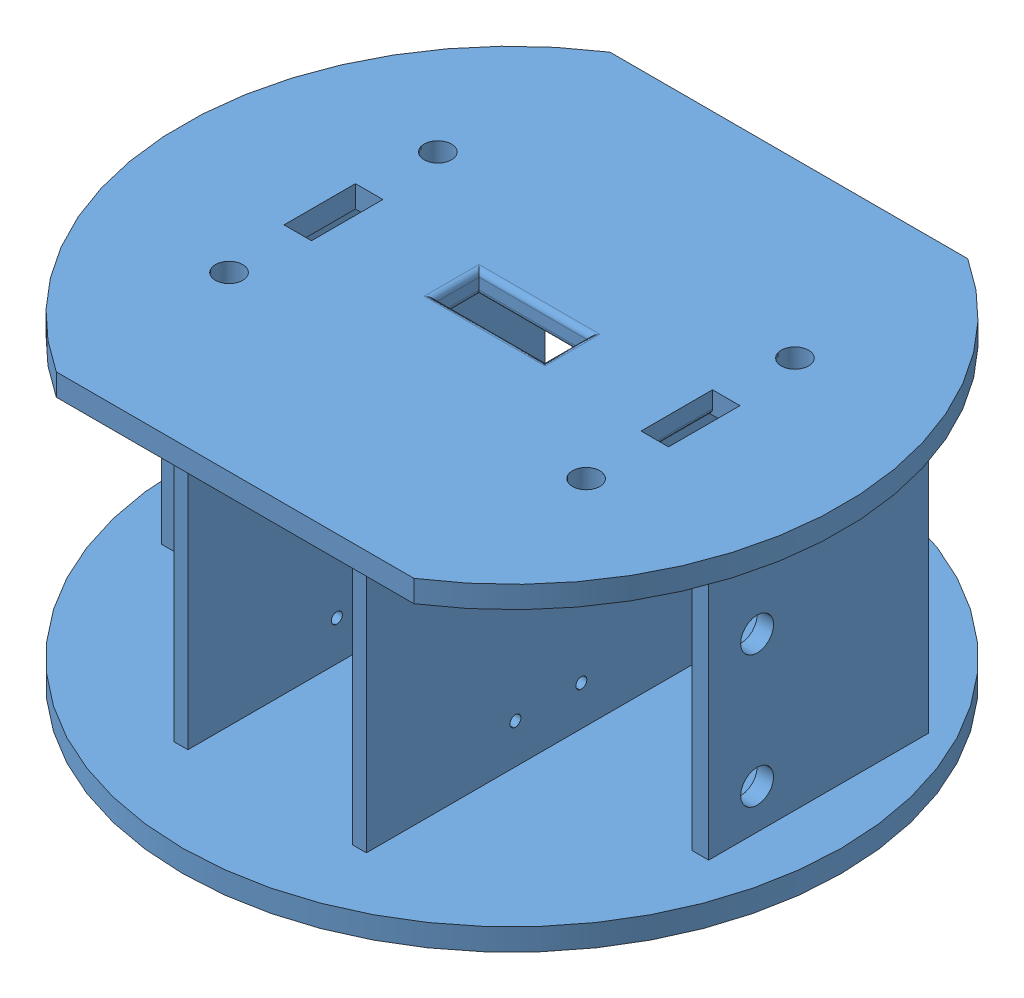
SolidWorks assembly NewMainBase, configuration Default. Lengths in mm.
Overall size (120 71.5 120).
2 component instances, 2 part files, 1 mates.
Components (placement in the parent):
- Main_Base-1: Main_Base [Default] at origin size (120 58 120)
- dovetail_female-1: dovetail_female [Default] at (0 -60.75 0) size (49 13.5 60)
Mates (geometry in assembly coordinates):
- Coincident1: coincident: point of dovetail_female-1
